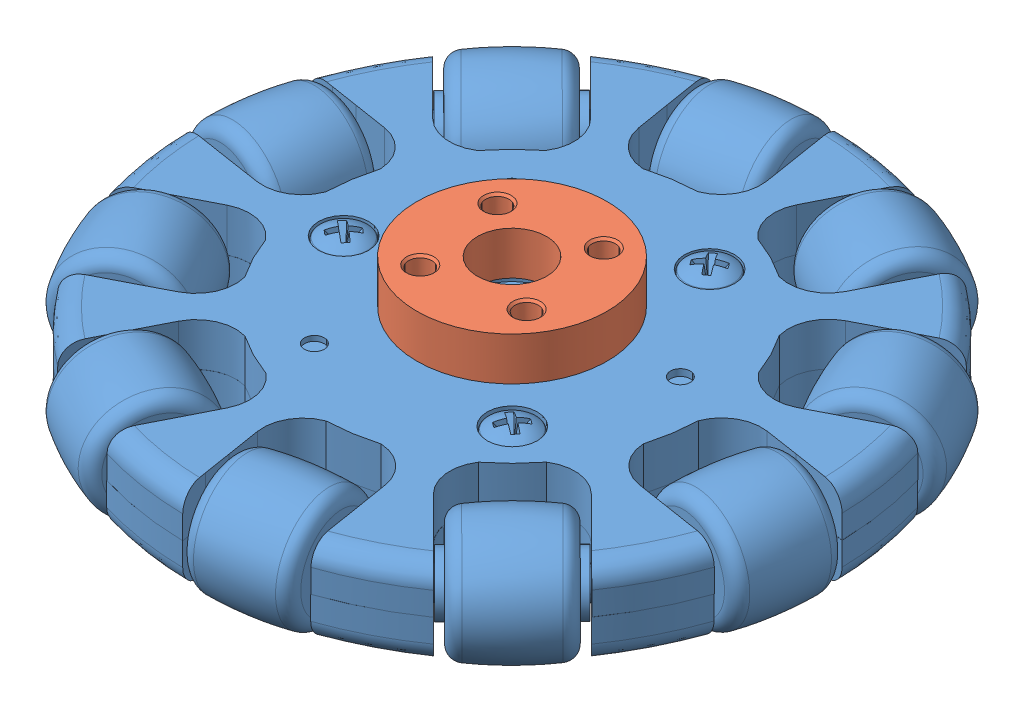
SolidWorks assembly Omni dual wheel spinner, configuration Default. Lengths in mm.
Overall size (77.7 16.71 77.72).
2 component instances, 2 part files, 3 mates.
Components (placement in the parent):
- 3-inch omni single wheel part-1: 3-inch omni single wheel part [Default] at (8.7963 -3.939 -0.2393) size (77.7 13.48 77.72)
- Omni wheel joining hub-1: Omni wheel joining hub [Default] at (1.7244 6.4355 -0.2049) x (0.809625 0 0.586947) z (0 -1 0) size (22 22 5)
Mates (geometry in assembly coordinates):
- Concentric3: concentric anti-aligned: cylinder of 3-inch omni single wheel part-1 through (1.7244 -1.0645 -0.2049) axis (0 1 0) radius 4; cylinder of Omni wheel joining hub-1 through (1.7244 8.9355 -0.2049) axis (0 -1 0) radius 4
- Coincident2: coincident anti-aligned: plane of 3-inch omni single wheel part-1 through (-11.9708 3.9355 22.6509) normal (0 1 0); plane of Omni wheel joining hub-1 through (1.7244 3.9355 -0.2049) normal (0 -1 0)
- Coincident11: coincident: point of 3-inch omni single wheel part-1; plane of Omni wheel joining hub-1
